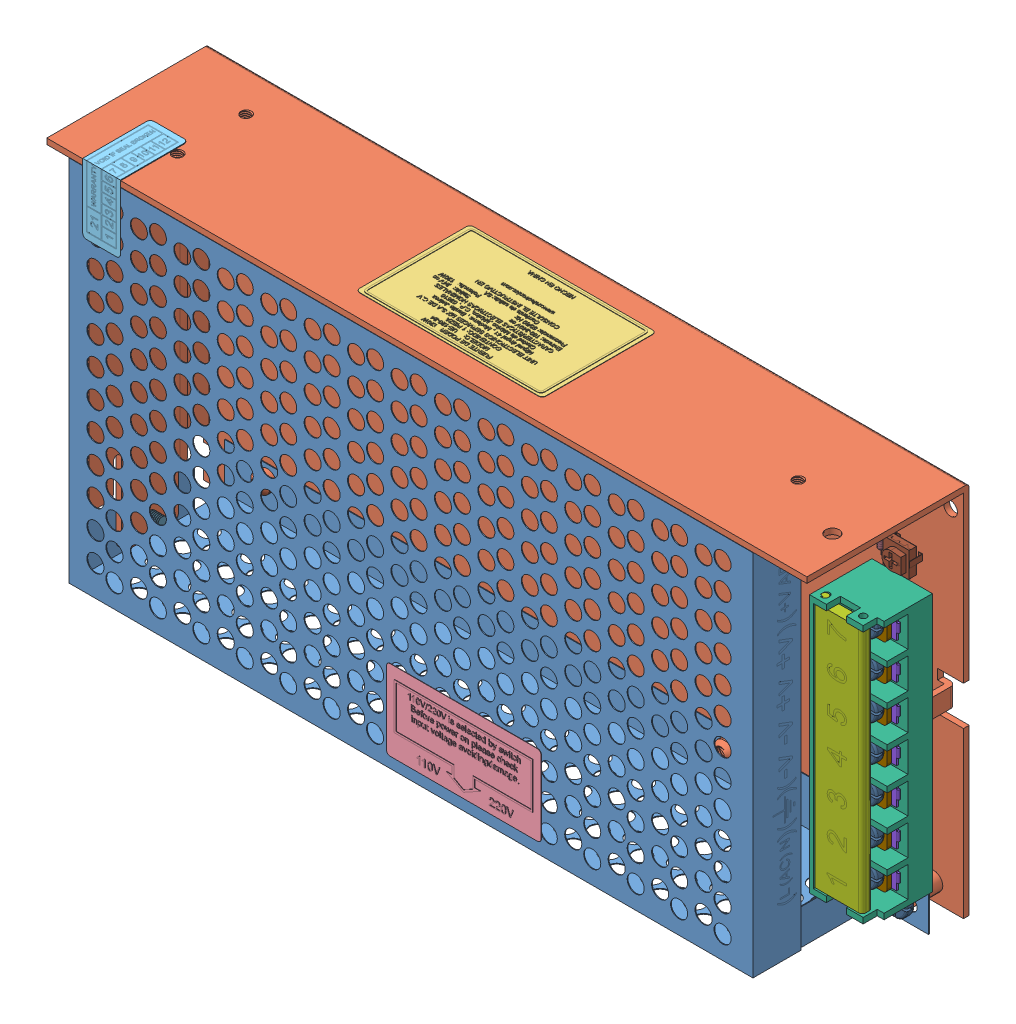
SolidWorks assembly Fuente conmutada 24V 5A, configuration Default. Lengths in mm.
Overall size (200 98.7 42.95).
35 component instances, 15 part files, 0 mates.
Components (placement in the parent):
- Fuente conmutada 24V 5A.step-1: Fuente conmutada 24V 5A.step [Default] at origin size (200 98.7 42.95)
  - Tapa Superior.step-1: Tapa Superior.step [Default] at (-4.2 -1.75 42.5) size (193.4 96.9 41.2)
  - Tapa Inferior.step-1: Tapa Inferior.step [Default] at origin size (200 98.55 42.75)
  - PCB.step-1: PCB.step [Default] at (3.75 -1.05 8.2) (suppressed, hidden)
  - Tarjeta tecnica 24V 5A.step-1: Tarjeta tecnica 24V 5A.step [Default] at (0 49.25 21.85) x (-1 0 0) z (0 1 0) size (49 30 0.2)
  - F3n de voltaje.step-1: F3n de voltaje.step [Default] at (9.8 -35.8 42.7) size (40.7 21.1 0.2)
  - Tarjeta lateral.step-1: Tarjeta lateral.step [Default] at (-85.5 40.45 42.7) x (0 1 0) z (0 0 1) size (18 9.9 17.8)
  - Bornera.step-1: Bornera.step [Default] at (92.05 -5.05 9.7) x (0 1 0) z (0 0 1) size (68.1 15.9 16.4)
  - Tapa bornera.step-1: Tapa bornera.step [Default] at (90.8 -5.05 22.85) x (0 1 0) z (0 0 1) size (68 13.4 2.8)
  - F3n para la bornera.step-1: F3n para la bornera.step [Default] at (92.55 -33.55 16.1) x (0 1 0) z (0 0 1) size (7.4 11 0.9)
  - F3n para la bornera.step-2: F3n para la bornera.step [Default] at (92.55 -24.05 16.1) x (0 1 0) z (0 0 1) size (7.4 11 0.9)
  - F3n para la bornera.step-3: F3n para la bornera.step [Default] at (92.55 -14.55 16.1) x (0 1 0) z (0 0 1) size (7.4 11 0.9)
  - F3n para la bornera.step-4: F3n para la bornera.step [Default] at (92.55 -5.05 16.1) x (0 1 0) z (0 0 1) size (7.4 11 0.9)
  - F3n para la bornera.step-5: F3n para la bornera.step [Default] at (92.55 4.45 16.1) x (0 1 0) z (0 0 1) size (7.4 11 0.9)
  - F3n para la bornera.step-6: F3n para la bornera.step [Default] at (92.55 13.95 16.1) x (0 1 0) z (0 0 1) size (7.4 11 0.9)
  - F3n para la bornera.step-7: F3n para la bornera.step [Default] at (92.55 23.45 16.1) x (0 1 0) z (0 0 1) size (7.4 11 0.9)
  - Tuerca.step-1: Tuerca.step [Default] at (92.55 -33.55 16.7) size (7.4 7.4 1.3)
  - Tuerca.step-2: Tuerca.step [Default] at (92.55 -24.05 16.7) size (7.4 7.4 1.3)
  - Tuerca.step-3: Tuerca.step [Default] at (92.55 -14.55 16.7) size (7.4 7.4 1.3)
  - Tuerca.step-4: Tuerca.step [Default] at (92.55 -5.05 16.7) size (7.4 7.4 1.3)
  - Tuerca.step-5: Tuerca.step [Default] at (92.55 4.45 16.7) size (7.4 7.4 1.3)
  - Tuerca.step-6: Tuerca.step [Default] at (92.55 13.95 16.7) size (7.4 7.4 1.3)
  - Tuerca.step-7: Tuerca.step [Default] at (92.55 23.45 16.7) size (7.4 7.4 1.3)
  - Tornillo.step-1: Tornillo.step [Default] at (92.5494 -33.6604 11.9) size (6.4 6.4 8.26)
  - Tornillo.step-2: Tornillo.step [Default] at (92.5494 -24.1604 11.9) size (6.4 6.4 8.26)
  - Tornillo.step-3: Tornillo.step [Default] at (92.5494 -14.6604 11.9) size (6.4 6.4 8.26)
  - Tornillo.step-4: Tornillo.step [Default] at (92.5494 -5.1604 11.9) size (6.4 6.4 8.26)
  - Tornillo.step-5: Tornillo.step [Default] at (92.5494 4.3396 11.9) size (6.4 6.4 8.26)
  - Tornillo.step-6: Tornillo.step [Default] at (92.55 13.95 11.9) size (6.4 6.4 8.26)
  - Tornillo.step-7: Tornillo.step [Default] at (92.55 23.45 11.9) size (6.4 6.4 8.26)
  - Boton Ajuste.step-1: Boton Ajuste.step [Default] at (94 35.95 11.1) x (0 1 0) z (0 0 1) size (6.7 7 5)
  - Led.step-1: Led.step [Default] at (89.5 42.45 10.4) x (0 1 0) z (0 0 1) size (3 3 6.5)
  - Resistencia.step-1: Resistencia.step [Default] at (87.5 33.45 10.7) x (0 1 0) z (0 0 1) size (8.6 1.5 1.75)
  - Tornillo.step-8: Tornillo.step [Default] at (92.1994 -44.6104 3.7) size (6.4 6.4 8.26)
  - Tornillo para sujetar la tapa superior.step-1: Tornillo para sujetar la tapa superior.step [Default] at (-89.5 -43 22.8) x (0 0 1) z (-1 0 0) size (6.1 6.1 6.24)
